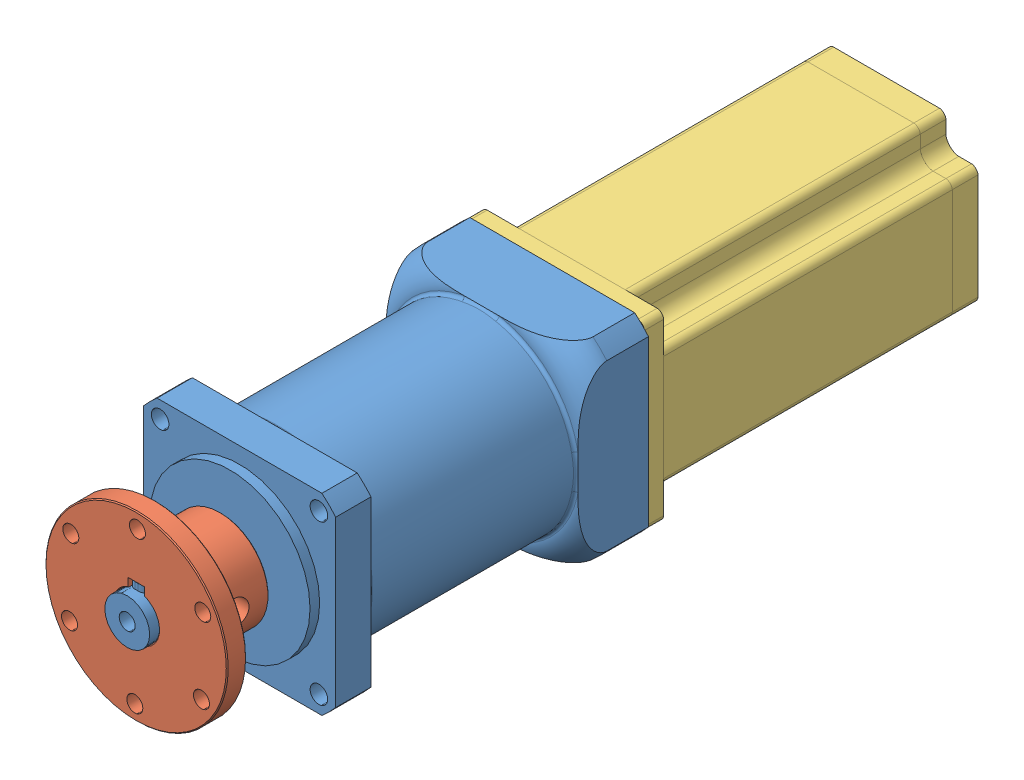
SolidWorks assembly Axe2, configuration Défaut. Lengths in mm.
Overall size (77.83 77.83 236.73).
3 component instances, 3 part files, 3 mates.
Components (placement in the parent):
- PLF60_50_1_reducer-1: PLF60_50_1_reducer [Défaut] at (-19.8116 37.9804 -66.25) size (77.83 77.83 132.5)
- D14_Hub-1: D14_Hub [Défaut] at (-19.8116 37.9804 63.4705) x (-1 0 0) z (0 -1 0) size (56.8 26.4 56.8)
- Nema23x100-1: Nema23x100 [Défaut] at (-19.8116 37.9804 -170.458) size (56.45 56.45 126.22)
Mates (geometry in assembly coordinates):
- Coaxiale1: concentric anti-aligned: cylinder of PLF60_50_1_reducer-1 through (-19.8116 37.9804 66.25) axis (0 0 -1) radius 7; cylinder of D14_Hub-1 through (-19.8116 37.9804 37.0705) axis (0 0 1) radius 7
- Parallèle1: parallel anti-aligned: plane of PLF60_50_1_reducer-1 through (-22.415 46.9804 43.25) normal (0 1 0); plane of D14_Hub-1 through (-22.3616 47.2804 63.4705) normal (0 -1 0)
- Coaxiale2: concentric aligned: cylinder of PLF60_50_1_reducer-1 through (-19.8116 37.9804 -35.25) axis (0 0 -1) radius 4; cylinder of Nema23x100-1 through (-19.8116 37.9804 -44.258) axis (0 0 -1) radius 4
